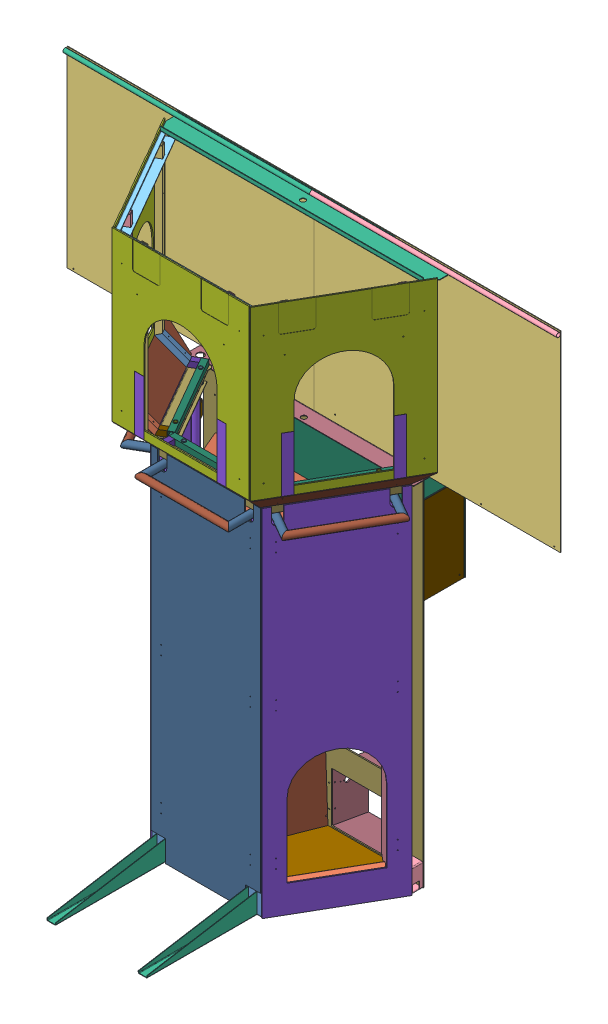
SolidWorks assembly GE-16004_ASM, configuration Default. Lengths in mm.
Overall size (2743.2 3118.93 1489.95).
150 component instances, 51 part files, 0 mates.
Components (placement in the parent):
- GE-16005_ASM-1: GE-16005_ASM [Default] at origin size (1219.2 203.2 1201.03)
  - GE-16005-01-1: GE-16005-01 [Default] at origin size (609.6 127 76.2)
  - GE-16005-02-1: GE-16005-02 [Default] at (304.8 63.5 38.1) x (0.5 0 -0.866025) z (0.866025 0 0.5) size (609.6 127 76.2)
  - GE-16005-03-1: GE-16005-03 [Default] at (-304.8 -63.5 38.1) x (-0.5 0 -0.866025) z (-0.866025 0 0.5) size (609.6 127 76.2)
  - GE-16005-04-1: GE-16005-04 [Default] at (609.6 63.5 -489.8291) x (0 0 -1) z (1 0 0) size (63.5 127 76.2)
  - GE-16005-05-1: GE-16005-05 [Default] at (-550.3537 -63.5 -450.7115) size (48.26 203.2 48.26)
  - GE-16005-06-1: GE-16005-06 [Default] at (254 -63.5 647.7) size (50.8 114.3 609.6)
  - GE-16005-06-2: GE-16005-06 [Default] at (-254 -63.5 647.7) size (50.8 114.3 609.6)
  - GE-16005-05-2: GE-16005-05 [Default] at (-309.0537 -63.5 -32.7676) size (48.26 203.2 48.26)
  - GE-16005-05-3: GE-16005-05 [Default] at (-241.3 -63.5 6.35) size (48.26 203.2 48.26)
  - GE-16005-05-4: GE-16005-05 [Default] at (241.3 -63.5 6.35) size (48.26 203.2 48.26)
  - GE-16005-05-5: GE-16005-05 [Default] at (309.0537 -63.5 -32.7676) size (48.26 203.2 48.26)
  - GE-16005-05-6: GE-16005-05 [Default] at (550.3537 -63.5 -450.7115) size (48.26 203.2 48.26)
  - GE-16005-07-1: GE-16005-07 [Default] at (-609.6 -63.5 -489.8291) x (0 0 -1) z (-1 0 0) size (63.5 127 76.2)
- GE-16006_ASM-1: GE-16006_ASM [Default] at (-241.3 -63.5 6.35) size (520.7 1981.2 190.5)
  - GE-16006-01-1: GE-16006-01 [Default] at origin size (38.1 1981.2 38.1)
  - GE-16006-02-1: GE-16006-02 [Default] at (6.35 838.2 0) size (469.9 38.1 38.1)
  - GE-16006-01-2: GE-16006-01 [Default] at (482.6 0 0) size (38.1 1981.2 38.1)
  - GE-16006-03-1: GE-16006-03 [Default] at (482.6 1911.35 6.35) size (38.1 38.1 165.1)
  - GE-16006-03-2: GE-16006-03 [Default] at (0 1911.35 6.35) x (-1 0 0) z (0 0 1) size (38.1 38.1 165.1)
  - GE-16006-04-1: GE-16006-04 [Default] at (-19.05 1911.35 152.4) size (520.7 38.1 38.1)
  - GE-16006-02-2: GE-16006-02 [Default] at (6.35 1962.15 0) size (469.9 38.1 38.1)
- GE-16006_ASM-2: GE-16006_ASM [Default] at (309.0537 -63.5 -32.7676) x (0.5 0 -0.866025) z (0.866025 0 0.5) size (520.7 1981.2 190.5)
  - GE-16006-01-1: GE-16006-01 [Default] at origin size (38.1 1981.2 38.1)
  - GE-16006-02-1: GE-16006-02 [Default] at (6.35 838.2 0) size (469.9 38.1 38.1)
  - GE-16006-01-2: GE-16006-01 [Default] at (482.6 0 0) size (38.1 1981.2 38.1)
  - GE-16006-03-1: GE-16006-03 [Default] at (482.6 1911.35 6.35) size (38.1 38.1 165.1)
  - GE-16006-03-2: GE-16006-03 [Default] at (0 1911.35 6.35) x (-1 0 0) z (0 0 1) size (38.1 38.1 165.1)
  - GE-16006-04-1: GE-16006-04 [Default] at (-19.05 1911.35 152.4) size (520.7 38.1 38.1)
  - GE-16006-02-2: GE-16006-02 [Default] at (6.35 1962.15 0) size (469.9 38.1 38.1)
- GE-16006_ASM-3: GE-16006_ASM [Default] at (-550.3537 -63.5 -450.7115) x (0.5 0 0.866025) z (-0.866025 0 0.5) size (520.7 1981.2 190.5)
  - GE-16006-01-1: GE-16006-01 [Default] at origin size (38.1 1981.2 38.1)
  - GE-16006-02-1: GE-16006-02 [Default] at (6.35 838.2 0) size (469.9 38.1 38.1)
  - GE-16006-01-2: GE-16006-01 [Default] at (482.6 0 0) size (38.1 1981.2 38.1)
  - GE-16006-03-1: GE-16006-03 [Default] at (482.6 1911.35 6.35) size (38.1 38.1 165.1)
  - GE-16006-03-2: GE-16006-03 [Default] at (0 1911.35 6.35) x (-1 0 0) z (0 0 1) size (38.1 38.1 165.1)
  - GE-16006-04-1: GE-16006-04 [Default] at (-19.05 1911.35 152.4) size (520.7 38.1 38.1)
  - GE-16006-02-2: GE-16006-02 [Default] at (6.35 1962.15 0) size (469.9 38.1 38.1)
- GE-16007_ASM-1: GE-16007_ASM [Default] at (0 1920.9512 34.8488) size (1270 85.8 603.25)
  - GE-16007-01-1: GE-16007-01 [Default] at origin size (1206.5 48.01 590.55)
  - GE-16007-02-1: GE-16007-02 [Default] at (0 3.175 -599.9988) x (1 0 0) z (0 1 0) size (1270 88.9 38.1)
- GE-16008_ASM-1: GE-16008_ASM [Default] at (-190.5 1847.9262 -25.4) size (514.35 1117.64 212.76)
  - GE-16008-01_AF0-1: GE-16008-01_AF0 [Default] at origin size (21.34 107.95 21.34)
  - GE-16008-02_AF0-1: GE-16008-02_AF0 [Default] at (-66.675 104.775 15.875) size (514.35 31.75 31.75)
  - GE-16008-01_AF1-1: GE-16008-01_AF1 [Default] at (381 0 0) size (21.34 107.95 21.34)
  - GE-16008-04_AF0-1: GE-16008-04_AF0 [Default] at (-34.925 73.025 66.675) x (-1 0 0) z (0 0 -1) size (31.75 31.75 50.8)
  - GE-16008-04_AF1-1: GE-16008-04_AF1 [Default] at (447.675 73.025 66.675) x (-1 0 0) z (0 0 -1) size (31.75 31.75 50.8)
  - GE-16008-03_AF0-1: GE-16008-03_AF0 [Default] at (-34.925 203.2387 196.8887) x (-1 0 0) z (0 -0.707107 0.707107) size (31.75 184.15 31.75)
  - GE-16008-03_AF1-1: GE-16008-03_AF1 [Default] at (415.925 73.025 66.675) x (1 0 0) z (0 -0.707107 0.707107) size (31.75 184.15 31.75)
  - GE-16008-05_AF0-1: GE-16008-05_AF0 [Default] at (-34.925 1117.6387 196.8887) x (-1 0 0) z (0 0 1) size (31.75 914.4 31.75)
  - GE-16008-05_AF1-1: GE-16008-05_AF1 [Default] at (447.675 1117.6387 196.8887) x (-1 0 0) z (0 0 1) size (31.75 914.4 31.75)
- GE-16008_ASM-2: GE-16008_ASM [Default] at (305.4435 1847.9262 -93.5079) x (0.5 0 -0.866025) z (0.866025 0 0.5) size (514.35 1117.64 212.76)
  - GE-16008-01_AF0-1: GE-16008-01_AF0 [Default] at origin size (21.34 107.95 21.34)
  - GE-16008-02_AF0-1: GE-16008-02_AF0 [Default] at (-66.675 104.775 15.875) size (514.35 31.75 31.75)
  - GE-16008-01_AF1-1: GE-16008-01_AF1 [Default] at (381 0 0) size (21.34 107.95 21.34)
  - GE-16008-04_AF0-1: GE-16008-04_AF0 [Default] at (-34.925 73.025 66.675) x (-1 0 0) z (0 0 -1) size (31.75 31.75 50.8)
  - GE-16008-04_AF1-1: GE-16008-04_AF1 [Default] at (447.675 73.025 66.675) x (-1 0 0) z (0 0 -1) size (31.75 31.75 50.8)
  - GE-16008-03_AF0-1: GE-16008-03_AF0 [Default] at (-34.925 203.2387 196.8887) x (-1 0 0) z (0 -0.707107 0.707107) size (31.75 184.15 31.75)
  - GE-16008-03_AF1-1: GE-16008-03_AF1 [Default] at (415.925 73.025 66.675) x (1 0 0) z (0 -0.707107 0.707107) size (31.75 184.15 31.75)
  - GE-16008-05_AF0-1: GE-16008-05_AF0 [Default] at (-34.925 1117.6387 196.8887) x (-1 0 0) z (0 0 1) size (31.75 914.4 31.75)
  - GE-16008-05_AF1-1: GE-16008-05_AF1 [Default] at (447.675 1117.6387 196.8887) x (-1 0 0) z (0 0 1) size (31.75 914.4 31.75)
- GE-16008_ASM-3: GE-16008_ASM [Default] at (-495.9435 1847.9262 -423.4635) x (0.5 0 0.866025) z (-0.866025 0 0.5) size (514.35 1117.64 212.76)
  - GE-16008-01_AF0-1: GE-16008-01_AF0 [Default] at origin size (21.34 107.95 21.34)
  - GE-16008-02_AF0-1: GE-16008-02_AF0 [Default] at (-66.675 104.775 15.875) size (514.35 31.75 31.75)
  - GE-16008-01_AF1-1: GE-16008-01_AF1 [Default] at (381 0 0) size (21.34 107.95 21.34)
  - GE-16008-04_AF0-1: GE-16008-04_AF0 [Default] at (-34.925 73.025 66.675) x (-1 0 0) z (0 0 -1) size (31.75 31.75 50.8)
  - GE-16008-04_AF1-1: GE-16008-04_AF1 [Default] at (447.675 73.025 66.675) x (-1 0 0) z (0 0 -1) size (31.75 31.75 50.8)
  - GE-16008-03_AF0-1: GE-16008-03_AF0 [Default] at (-34.925 203.2387 196.8887) x (-1 0 0) z (0 -0.707107 0.707107) size (31.75 184.15 31.75)
  - GE-16008-03_AF1-1: GE-16008-03_AF1 [Default] at (415.925 73.025 66.675) x (1 0 0) z (0 -0.707107 0.707107) size (31.75 184.15 31.75)
  - GE-16008-05_AF0-1: GE-16008-05_AF0 [Default] at (-34.925 1117.6387 196.8887) x (-1 0 0) z (0 0 1) size (31.75 914.4 31.75)
  - GE-16008-05_AF1-1: GE-16008-05_AF1 [Default] at (447.675 1117.6387 196.8887) x (-1 0 0) z (0 0 1) size (31.75 914.4 31.75)
- GE-16009_ASM-1: GE-16009_ASM [Default] at (0 2905.3161 173.0635) size (1524 88.9 736.6)
  - GE-16009-01-1: GE-16009-01 [Default] at origin size (1524 63.5 685.31)
  - GE-16009-02-1: GE-16009-02 [Default] at (0 63.5 -669.8488) x (0 0 1) z (-1 0 0) size (127 25.4 1524)
- GE-16067-1: GE-16067 [Default] at (568.0291 2517.775 -154.5421) x (-0.5 0 0.866025) z (0.866025 0 0.5) size (762 933.45 6.35)
- GE-16067-2: GE-16067 [Default] at (-6.35 2517.775 171.4887) x (-1 0 0) z (0 0 1) size (762 933.45 6.35)
- GE-16067-3: GE-16067 [Default] at (-574.3791 2517.775 -165.5406) x (-0.5 0 -0.866025) z (-0.866025 0 0.5) size (762 933.45 6.35)
- GE-16068_ASM-1: GE-16068_ASM [Default] at (462.6993 923.925 -222.6895) x (-0.5 0 0.866025) z (-0.866025 0 -0.5) size (609.6 1974.85 60.33)
  - GE-16069-1: GE-16069 [Default] at origin size (609.6 1974.85 6.35)
  - GE-16070-1: GE-16070 [Default] at (263.525 752.475 6.35) x (0 0 -1) z (1 0 0) size (53.98 76.2 31.75)
  - GE-16070-2: GE-16070 [Default] at (263.525 -9.525 6.35) x (0 0 -1) z (1 0 0) size (53.98 76.2 31.75)
  - GE-16070-3: GE-16070 [Default] at (263.525 -771.525 6.35) x (0 0 -1) z (1 0 0) size (53.98 76.2 31.75)
  - GE-16070-4: GE-16070 [Default] at (-263.525 828.675 6.35) x (0 0 -1) z (-1 0 0) size (53.98 76.2 31.75)
  - GE-16070-5: GE-16070 [Default] at (-263.525 66.675 6.35) x (0 0 -1) z (-1 0 0) size (53.98 76.2 31.75)
  - GE-16070-6: GE-16070 [Default] at (-263.525 -695.325 6.35) x (0 0 -1) z (-1 0 0) size (53.98 76.2 31.75)
- GE-16068_ASM-2: GE-16068_ASM [Default] at (-462.6993 923.925 -222.6895) x (-0.5 0 -0.866025) z (0.866025 0 -0.5) size (609.6 1974.85 60.33)
  - GE-16069-1: GE-16069 [Default] at origin size (609.6 1974.85 6.35)
  - GE-16070-1: GE-16070 [Default] at (263.525 752.475 6.35) x (0 0 -1) z (1 0 0) size (53.98 76.2 31.75)
  - GE-16070-2: GE-16070 [Default] at (263.525 -9.525 6.35) x (0 0 -1) z (1 0 0) size (53.98 76.2 31.75)
  - GE-16070-3: GE-16070 [Default] at (263.525 -771.525 6.35) x (0 0 -1) z (1 0 0) size (53.98 76.2 31.75)
  - GE-16070-4: GE-16070 [Default] at (-263.525 828.675 6.35) x (0 0 -1) z (-1 0 0) size (53.98 76.2 31.75)
  - GE-16070-5: GE-16070 [Default] at (-263.525 66.675 6.35) x (0 0 -1) z (-1 0 0) size (53.98 76.2 31.75)
  - GE-16070-6: GE-16070 [Default] at (-263.525 -695.325 6.35) x (0 0 -1) z (-1 0 0) size (53.98 76.2 31.75)
- GE-16071_ASM-1: GE-16071_ASM [Default] at (0 923.925 44.45) x (-1 0 0) z (0 0 -1) size (609.6 1974.85 60.33)
  - GE-16072-1: GE-16072 [Default] at origin size (609.6 1974.85 6.35)
  - GE-16070-1: GE-16070 [Default] at (263.525 752.475 6.35) x (0 0 -1) z (1 0 0) size (53.98 76.2 31.75)
  - GE-16070-2: GE-16070 [Default] at (263.525 -9.525 6.35) x (0 0 -1) z (1 0 0) size (53.98 76.2 31.75)
  - GE-16070-3: GE-16070 [Default] at (263.525 -771.525 6.35) x (0 0 -1) z (1 0 0) size (53.98 76.2 31.75)
  - GE-16070-4: GE-16070 [Default] at (-263.525 828.675 6.35) x (0 0 -1) z (-1 0 0) size (53.98 76.2 31.75)
  - GE-16070-5: GE-16070 [Default] at (-263.525 66.675 6.35) x (0 0 -1) z (-1 0 0) size (53.98 76.2 31.75)
  - GE-16070-6: GE-16070 [Default] at (-263.525 -695.325 6.35) x (0 0 -1) z (-1 0 0) size (53.98 76.2 31.75)
- GE-16073-1: GE-16073 [Default] at (455.2607 1920.9512 -219.6489) x (0.5 0 -0.866025) z (0.612372 -0.707107 0.353553) size (762 184.15 6.35)
- GE-16073-2: GE-16073 [Default] at (-6.35 1920.9512 41.275) x (1 0 0) z (0 -0.707107 0.707107) size (762 184.15 6.35)
- GE-16073-3: GE-16073 [Default] at (-461.6107 1920.9512 -230.6475) x (0.5 0 0.866025) z (-0.612372 -0.707107 0.353553) size (762 184.15 6.35)
- GE-16097_ASM-1: GE-16097_ASM [Default] at (0 927.1 -553.3291) x (-1 0 0) z (0 0 -1) size (1219.2 1981.2 288.93)
  - GE-16098-1: GE-16098 [Default] at origin size (1219.2 1981.2 6.35)
  - GE-16099-1: GE-16099 [Default] at (-241.3 -987.8833 206.4629) x (1 0 0) z (0 -1 0) size (292.1 200.11 331.89)
  - GE-16099-2: GE-16099 [Default] at (241.3 -987.8833 206.4629) x (1 0 0) z (0 -1 0) size (292.1 200.11 331.89)
  - GE-16100-1: GE-16100 [Default] at (-546.1 806.45 6.35) size (14.66 12.7 279.4)
  - GE-16100-2: GE-16100 [Default] at (-546.1 347.3657 6.35) size (14.66 12.7 279.4)
  - GE-16100-3: GE-16100 [Default] at (-157.4232 284.6759 6.35) size (14.66 12.7 279.4)
  - GE-16100-4: GE-16100 [Default] at (231.2537 221.9861 6.35) size (14.66 12.7 279.4)
  - GE-16100-5: GE-16100 [Default] at (546.1 222.25 6.35) size (14.66 12.7 279.4)
  - GE-16100-6: GE-16100 [Default] at (546.1 806.45 6.35) size (14.66 12.7 279.4)
  - GE-16101-1: GE-16101 [Default] at (-558.8 819.15 285.75) size (1117.6 609.6 3.17)
  - GE-16102-1: GE-16102 [Default] at (393.7 209.55 285.75) size (279.4 152.4 279.4)
  - GE-16103-1: GE-16103 [Default] at (-552.45 354.822 9.525) x (0.987241 -0.159232 0) z (0 0 1) size (800.1 3.17 273.05)
  - GE-16104-1: GE-16104 [Default] at (-556.6073 336.55 282.575) size (3.17 482.6 273.05)
  - GE-16105-1: GE-16105 [Default] at (553.4323 209.55 282.575) size (3.17 609.6 273.05)
- GE-16106-1: GE-16106 [Default] at (-254 1382.7054 -1252.8873) x (0 -0.258819 -0.965926) z (1 0 0) size (504.83 6.35 1016)
- GE-16107_ASM-1: GE-16107_ASM [Default] at (685.8 2463.0767 -560.2091) x (-1 0 0) z (0 0 -1) size (2743.2 1066.8 26.59)
  - GE-16108-1: GE-16108 [Default] at origin size (1371.6 1066.8 3.17)
  - GE-16109-1: GE-16109 [Default] at (685.8 520.7 -14.8844) x (-1 0 0) z (0 0 1) size (1371.6 23.42 23.42)
  - GE-16111-1: GE-16111 [Default] at (584.2 520.7 -14.8844) size (203.2 19.05 19.05)
  - GE-16110-1: GE-16110 [Default] at (685.8 520.7 -14.8844) size (1371.6 23.42 23.42)
  - GE-16108-2: GE-16108 [Default] at (1371.6 0 -3.175) x (-1 0 0) z (0 0 -1) size (1371.6 1066.8 3.17)
- GE-16004-01_ASM-1: GE-16004-01_ASM [Default] at (-580.5658 2073.275 -161.9687) x (0.5 0 0.866025) z (0 -1 0) size (508 0.79 304.8)
  - GE-16004-02-1: GE-16004-02 [Default] at origin size (406.4 0.79 44.45)
  - GE-16004-03-1: GE-16004-03 [Default] at (-228.6 0 -130.175) x (0 0 -1) z (1 0 0) size (304.8 0.79 50.8)
  - GE-16004-03-2: GE-16004-03 [Default] at (228.6 0 -130.175) x (0 0 -1) z (1 0 0) size (304.8 0.79 50.8)
- GE-16004-01_ASM-2: GE-16004-01_ASM [Default] at (-6.35 2073.275 178.6325) x (1 0 0) z (0 -1 0) size (508 0.79 304.8)
  - GE-16004-02-1: GE-16004-02 [Default] at origin size (406.4 0.79 44.45)
  - GE-16004-03-1: GE-16004-03 [Default] at (-228.6 0 -130.175) x (0 0 -1) z (1 0 0) size (304.8 0.79 50.8)
  - GE-16004-03-2: GE-16004-03 [Default] at (228.6 0 -130.175) x (0 0 -1) z (1 0 0) size (304.8 0.79 50.8)
- GE-16004-01_ASM-3: GE-16004-01_ASM [Default] at (574.2158 2073.275 -150.9702) x (0.5 0 -0.866025) z (0 -1 0) size (508 0.79 304.8)
  - GE-16004-02-1: GE-16004-02 [Default] at origin size (406.4 0.79 44.45)
  - GE-16004-03-1: GE-16004-03 [Default] at (-228.6 0 -130.175) x (0 0 -1) z (1 0 0) size (304.8 0.79 50.8)
  - GE-16004-03-2: GE-16004-03 [Default] at (228.6 0 -130.175) x (0 0 -1) z (1 0 0) size (304.8 0.79 50.8)
- GE-16112_ASM-1: GE-16112_ASM [Default] at (252.9553 64.5348 -39.0705) x (-1 0 0) z (0 -0.988252 0.152831) size (1127.07 666.61 931.34)
  - GE-16113-1: GE-16113 [Default] at origin size (1021.26 508 6.35)
  - GE-16114-1: GE-16114 [Default] at (759.1329 447.675 6.35) x (0.866025 -0.5 0) z (0.5 0.866025 0) size (6.35 101.6 355.6)
  - GE-16114-2: GE-16114 [Default] at (-256.6322 444.5 6.35) x (0.866025 0.5 0) z (-0.5 0.866025 0) size (6.35 101.6 355.6)
  - GE-16115-1: GE-16115 [Default] at (163.6378 351.1437 -823.3926) x (0.176771 -0.966864 0.184188) z (-0.984252 -0.173648 0.03308) size (508 838.2 6.35)
  - GE-16116-1: GE-16116 [Default] at (163.6378 456.0171 -35.3466) x (1 0 0) z (0 0.187135 0.982334) size (190.5 44.45 44.45)
  - GE-16115-2: GE-16115 [Default] at (360.3329 349.7549 -823.1254) x (-0.185667 -0.965198 0.184177) z (-0.982613 0.182387 -0.034745) size (508 838.2 6.35)
  - GE-16117-1: GE-16117 [Default] at (638.1063 525.4846 -12.1076) x (0.756757 -0.646017 0.099905) z (0.653697 0.747867 -0.115656) size (234.95 508 6.35)
  - GE-16117-2: GE-16117 [Default] at (-128.0447 520.0211 -2.267) x (-0.761876 -0.640114 0.098992) z (0.647723 -0.752926 0.116438) size (234.95 508 6.35)
  - GE-16118-1: GE-16118 [Default] at (-251.1329 447.675 6.35) x (0.5 -0.866025 0) z (0 0 1) size (355.6 25.4 25.4)
  - GE-16118-2: GE-16118 [Default] at (581.3329 139.7164 6.35) x (0.5 0.866025 0) z (0 0 1) size (355.6 25.4 25.4)
  - GE-16119-1: GE-16119 [Default] at (505.3678 508 50.8) x (-1 0 0) z (0 -1 0) size (508 44.45 44.45)
